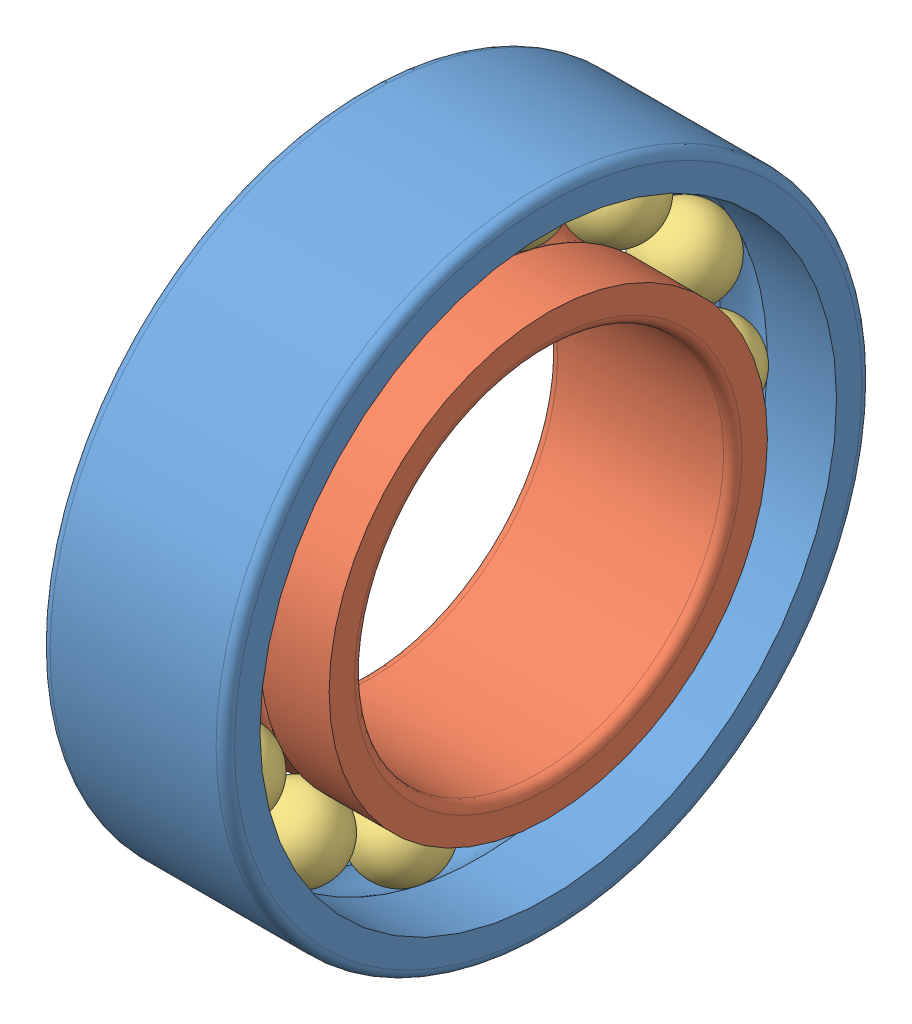
SolidWorks assembly Assem2, configuration Default. Lengths in mm.
Overall size (2.45 7 7).
16 component instances, 3 part files, 0 mates.
Components (placement in the parent):
- MR74_Outer_Ring-1: MR74_Outer_Ring [Default] at origin size (2 7 7)
- MR74_Inner_Ring-1: MR74_Inner_Ring [Default] x (1 0 0) z (0 -1 0) size (2 4.75 4.75)
- MR74_Ball-1: MR74_Ball [Default] at (1 0 2.75) x (1 0 0) z (0 -1 0) size (0.9 0.9 0.9)
- MR74_Ball-2: MR74_Ball [Default] at (1 -1.1932 2.4777) x (1 0 0) z (0 -1 0) size (0.9 0.9 0.9)
- MR74_Ball-3: MR74_Ball [Default] at (1 -2.15 1.7146) x (1 0 0) z (0 -1 0) size (0.9 0.9 0.9)
- MR74_Ball-4: MR74_Ball [Default] at (1 -2.6811 0.6119) x (1 0 0) z (0 -1 0) size (0.9 0.9 0.9)
- MR74_Ball-5: MR74_Ball [Default] at (1 -2.6811 -0.6119) x (1 0 0) z (0 -1 0) size (0.9 0.9 0.9)
- MR74_Ball-6: MR74_Ball [Default] at (1 -2.15 -1.7146) x (1 0 0) z (0 -1 0) size (0.9 0.9 0.9)
- MR74_Ball-7: MR74_Ball [Default] at (1 -1.1932 -2.4777) x (1 0 0) z (0 -1 0) size (0.9 0.9 0.9)
- MR74_Ball-8: MR74_Ball [Default] at (1 0 -2.75) x (1 0 0) z (0 -1 0) size (0.9 0.9 0.9)
- MR74_Ball-9: MR74_Ball [Default] at (1 1.1932 -2.4777) x (1 0 0) z (0 -1 0) size (0.9 0.9 0.9)
- MR74_Ball-10: MR74_Ball [Default] at (1 2.15 -1.7146) x (1 0 0) z (0 -1 0) size (0.9 0.9 0.9)
- MR74_Ball-11: MR74_Ball [Default] at (1 2.6811 -0.6119) x (1 0 0) z (0 -1 0) size (0.9 0.9 0.9)
- MR74_Ball-12: MR74_Ball [Default] at (1 2.6811 0.6119) x (1 0 0) z (0 -1 0) size (0.9 0.9 0.9)
- MR74_Ball-13: MR74_Ball [Default] at (1 2.15 1.7146) x (1 0 0) z (0 -1 0) size (0.9 0.9 0.9)
- MR74_Ball-14: MR74_Ball [Default] at (1 1.1932 2.4777) x (1 0 0) z (0 -1 0) size (0.9 0.9 0.9)
